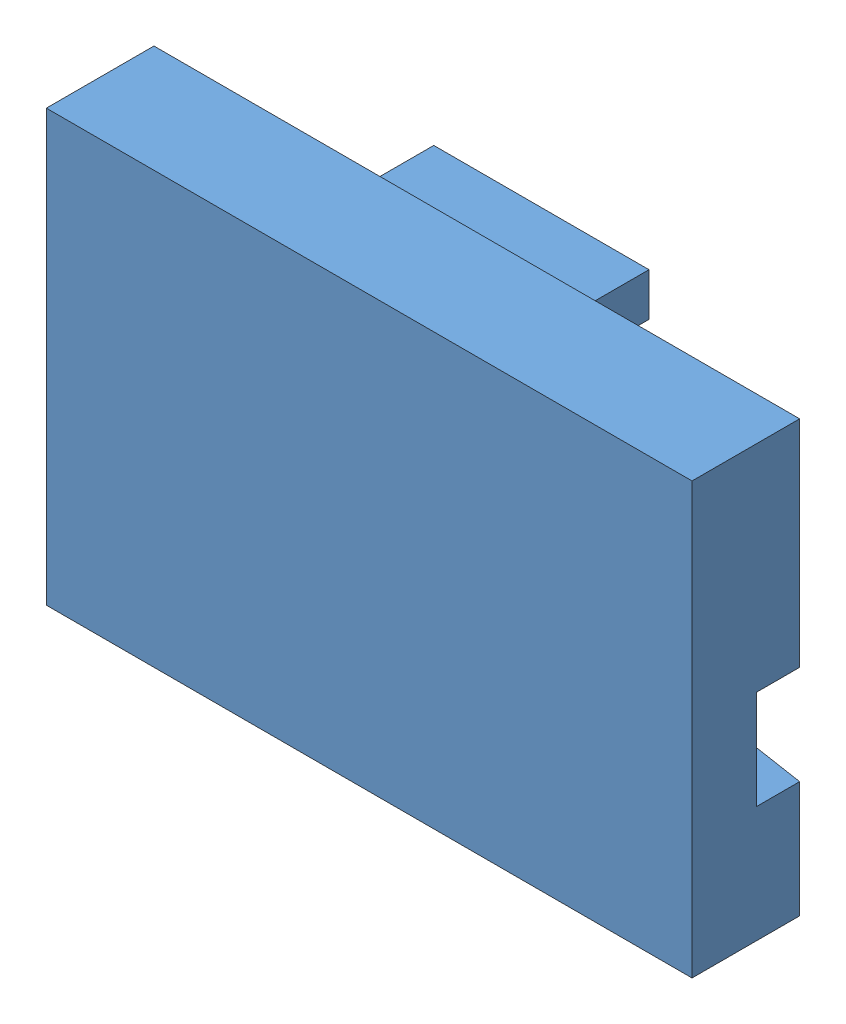
SolidWorks assembly all, configuration Default. Lengths in mm.
Overall size (30 20 8.62).
3 component instances, 3 part files, 4 mates.
Components (placement in the parent):
- ttttttttttt-3: ttttttttttt [Default] at (-2.19 -0.219 -31) size (30 20 8.62)
- Hand-3: Hand [Predeterminado] at (-66.8095 -63.4605 -32.8208) size (22.75 11.88 7.34)
- 44-2: 44 [Default] at (-2.19 -0.219 -31) size (30 20 8) (hidden)
Mates (geometry in assembly coordinates):
- Coincident10: coincident anti-aligned: plane of ttttttttttt-3 through (-2.19 -0.219 -31) normal (0 0 -1); plane of 44-2 through (-2.19 -0.219 -31) normal (0 0 1)
- Coincident11: coincident anti-aligned: plane of ttttttttttt-3 through (2.81 9.281 -34) normal (0 1 0); plane of 44-2 through (-2.19 9.281 -34) normal (0 -1 0)
- Coincident12: coincident anti-aligned: plane of ttttttttttt-3 through (2.81 -9.719 -28) normal (0 1 0); plane of 44-2 through (-2.19 -9.719 -28) normal (0 -1 0)
- Coincident13: coincident aligned: line of ttttttttttt-3 through (-17.19 9.781 -31) axis (0 -1 0); line of 44-2 through (-17.19 9.781 -31) axis (0 -1 0)
